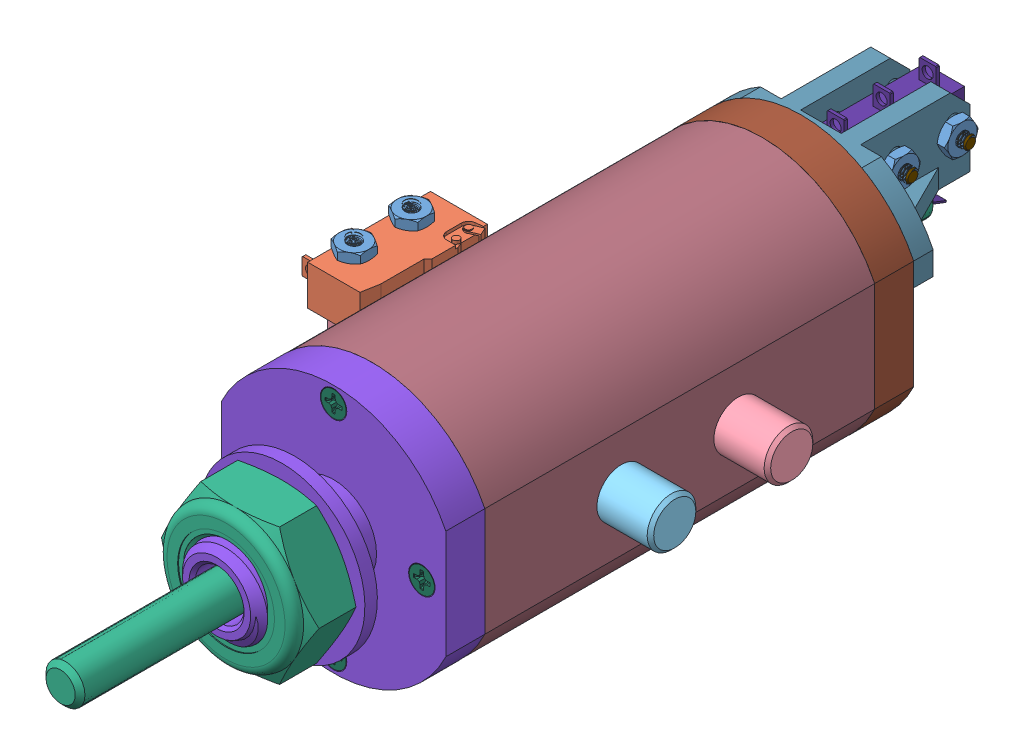
SolidWorks assembly Wing Fold Handle Mechanism, configuration Default. Lengths in mm.
Overall size (71.41 40.64 162.07).
63 component instances, 27 part files, 3 mates.
Components (placement in the parent):
- Wing Fold Mechanism Rotating ASSY-1: Wing Fold Mechanism Rotating ASSY [Default] at origin size (19.05 19.05 139.7)
  - Wing Fold Mechanism Rotary Detents-1: Wing Fold Mechanism Rotary Detents [Default] at origin size (19.05 19.05 19.05)
    - Wing Fold Mechanism Rotary Detents-1: Wing Fold Mechanism Rotary Detents [Default] at origin size (19.05 19.05 19.05)
    - 92311A105-1: 92311A105 [Default] at (-4.0904 4.0904 33.3375) x (0.707107 0.707107 0) z (-0.707107 0.707107 0) size (2.91 2.9 4.84)
    - 91841A005-1: 91841A005 [Default] at (-4.0972 4.0972 33.3375) x (0.707107 0.707107 0) z (0 0 1) size (6.35 2.56 7.33)
    - 92311A105-2: 92311A105 [Default] at (-4.0904 4.0904 23.8125) x (0.707107 0.707107 0) z (-0.707107 0.707107 0) size (2.91 2.9 4.84)
    - 91841A005-2: 91841A005 [Default] at (-4.0972 4.0972 23.8125) x (0.707107 0.707107 0) z (0 0 1) size (6.35 2.56 7.33)
  - Wing Fold Mechanism Push-Pull Detents-1: Wing Fold Mechanism Push-Pull Detents [Default] at origin size (19.05 19.05 19.05)
    - Wing Fold Mechanism Push-Pull Detents-1: Wing Fold Mechanism Push-Pull Detents [Default] at origin size (19.05 19.05 19.05)
    - 91841A005-1: 91841A005 [Default] at (-4.0972 4.0972 14.2875) x (0.707107 0.707107 0) z (0 0 1) size (6.35 2.56 7.33)
    - 92311A105-1: 92311A105 [Default] at (-4.0904 4.0904 14.2875) x (0.707107 0.707107 0) z (-0.707107 0.707107 0) size (2.91 2.9 4.84)
  - 9414T6-1: 9414T6 [Default] at (0 0 -3.5719) x (0.707107 -0.707107 0) z (0 0 1) size (12.7 12.7 7.15)
  - 9414T6-2: 9414T6 [Default] at (0 0 41.6719) size (12.7 12.7 7.15)
  - Wing Fold Mechanism .250 Shaft-1: Wing Fold Mechanism .250 Shaft [Default] at origin size (6.35 6.35 139.7)
  - 92311A425-1: 92311A425 [Default] at (4.771 4.771 -3.5719) x (0.707107 -0.707107 0) z (0.707107 0.707107 0) size (4.96 4.83 6.49)
- Wing Fold Mechanism Body-1: Wing Fold Mechanism Body [Default] at origin size (59.65 40.64 121.3)
  - Wing Fold Mechanism Upper Cap-1: Wing Fold Mechanism Upper Cap [Default] at origin size (36.58 40.64 28.08)
    - Wing Fold Mechanism Upper Cap-1: Wing Fold Mechanism Upper Cap [Default] at origin size (36.58 40.64 28.08)
    - 6338K411-1: 6338K411 [Default] at (0 0 55.5625) x (1 0 0) z (0 -1 0) size (12.7 6.35 12.7)
    - 93365A112-1: 93365A112 [Default] at (0 -11.1125 61.9125) x (1 0 0) z (0 -1 0) size (3.58 4.78 3.58)
  - Wing Fold Mechanism Lower Cap-1: Wing Fold Mechanism Lower Cap [Default] at origin size (36.58 40.64 13.97)
    - Wing Fold Mechanism Lower Cap-1: Wing Fold Mechanism Lower Cap [Default] at origin size (36.58 40.64 13.97)
    - 6338K411 (1)-1: 6338K411 (1) [Default] at (0 0 -7.9375) x (1 0 0) z (0 1 0) size (12.7 6.35 12.7)
    - 93365A112-1: 93365A112 [Default] at (11.938 11.43 -14.2875) x (1 0 0) z (0 1 0) size (3.58 4.78 3.58)
    - 93365A112-2: 93365A112 [Default] at (-11.938 11.43 -14.2875) x (1 0 0) z (0 1 0) size (3.58 4.78 3.58)
  - Wing Fold Mechanism Main Shell-1: Wing Fold Mechanism Main Shell [Default] at origin size (46.86 40.64 63.5)
    - Wing Fold Mechanism Main Body-1: Wing Fold Mechanism Main Body [Default] at origin size (46.86 40.64 63.5)
    - 93365A112-1: 93365A112 [Default] at (-14.378 0 55.5625) x (1 0 0) z (0 -1 0) size (3.58 4.78 3.58)
    - 93365A112-2: 93365A112 [Default] at (0 17.68 55.5625) x (1 0 0) z (0 -1 0) size (3.58 4.78 3.58)
    - 93365A112-3: 93365A112 [Default] at (14.378 0 55.5625) x (1 0 0) z (0 -1 0) size (3.58 4.78 3.58)
    - 93365A112-4: 93365A112 [Default] at (0 -17.68 55.5625) x (1 0 0) z (0 -1 0) size (3.58 4.78 3.58)
    - 93365A112-5: 93365A112 [Default] at (-14.378 0 -7.9375) x (1 0 0) z (0 1 0) size (3.58 4.78 3.58)
    - 93365A112-6: 93365A112 [Default] at (14.378 0 -7.9375) x (1 0 0) z (0 1 0) size (3.58 4.78 3.58)
    - 93365A112-7: 93365A112 [Default] at (0 -17.68 -7.9375) x (1 0 0) z (0 1 0) size (3.58 4.78 3.58)
    - 93365A112-8: 93365A112 [Default] at (0 17.68 -7.9375) x (1 0 0) z (0 1 0) size (3.58 4.78 3.58)
  - Wing Fold Mechanism Locking Limit Switch Bracket-1: Wing Fold Mechanism Locking Limit Switch Bracket [Default] at origin size (36.58 12.7 20.96)
  - 96640A027-1: 96640A027 [Default] at (-14.378 0 60.6171) size (4.11 4.11 12.73)
  - 96640A027-2: 96640A027 [Default] at (0 -17.68 60.6171) size (4.11 4.11 12.73)
  - 96640A027-3: 96640A027 [Default] at (0 17.68 60.6171) size (4.11 4.11 12.73)
  - 96640A027-4: 96640A027 [Default] at (14.378 0 60.6171) size (4.11 4.11 12.73)
  - 96640A027-5: 96640A027 [Default] at (0 -17.68 -12.9921) x (1 0 0) z (0 0 -1) size (4.11 4.11 12.73)
  - 96640A027-6: 96640A027 [Default] at (0 17.68 -12.9921) x (1 0 0) z (0 0 -1) size (4.11 4.11 12.73)
  - 96640A027-7: 96640A027 [Default] at (14.378 0 -12.9921) x (1 0 0) z (0 0 -1) size (4.11 4.11 12.73)
  - 96640A027-8: 96640A027 [Default] at (-14.378 0 -12.9921) x (1 0 0) z (0 0 -1) size (4.11 4.11 12.73)
  - 91249A050-1: 91249A050 [Default] at (-11.938 11.43 -11.1125) x (1 0 0) z (0 0 -1) size (4.25 4.24 8)
  - 91249A050-2: 91249A050 [Default] at (11.938 11.43 -11.1125) x (1 0 0) z (0 0 -1) size (4.25 4.24 8)
  - 7658K15-1: 7658K15 [Default] at (-0.0508 14.2684 -27.6606) x (0 0 -1) z (-1 0 0) size (19.99 19.56 6.5)
  - 91249A060-1: 91249A060 [Default] at (9.398 11.9062 -23.0505) x (0 0 -1) z (-1 0 0) size (12.29 12.29 20.87)
  - 91249A060-2: 91249A060 [Default] at (9.398 11.9062 -32.4485) x (0 0 -1) z (-1 0 0) size (12.29 12.29 20.87)
  - 91841A003-1: 91841A003 [Default] at (7.2708 11.9062 -23.0505) x (0 -1 0) z (0 0 1) size (4.76 1.72 5.5)
  - 91841A003-2: 91841A003 [Default] at (7.2708 11.9062 -32.4485) x (0 -1 0) z (0 0 1) size (4.76 1.72 5.5)
  - 7658K16-1: 7658K16 [Default] at (-28.3972 8.1042 27.7241) x (0 0 1) z (0 1 0) size (19.99 24.56 6.5)
  - 7658K16-2: 7658K16 [Default] at (-28.3972 -8.1042 27.7241) x (0 0 1) z (0 1 0) size (19.99 24.56 6.5)
  - 91249A066-1: 91249A066 [Default] at (-26.035 14.0446 23.1521) x (1 0 0) z (0 -1 0) size (12.46 12.46 36.26)
  - 91249A066-2: 91249A066 [Default] at (-26.035 14.0446 32.512) x (1 0 0) z (0 -1 0) size (12.46 12.46 36.26)
  - 91841A003-3: 91841A003 [Default] at (-26.035 12.1491 23.1521) x (-1 0 0) z (0 0 -1) size (4.76 1.72 5.5)
  - 91841A003-4: 91841A003 [Default] at (-26.035 12.1491 32.512) x (-1 0 0) z (0 0 -1) size (4.76 1.72 5.5)
  - 84835A44-1: 84835A44 [Default] at (17.1196 0 14.2875) x (0 1 0) z (0 0 -1) size (9.53 19.76 9.53)
  - 84835A36-1: 84835A36 [Default] at (17.1196 0 33.3375) x (0 1 0) z (0 0 -1) size (9.53 19.76 9.53)
- Wing Fold Handle Retaining Nut-1: Wing Fold Handle Retaining Nut [Default] at (0 0 2.032) size (25.66 23.83 11.45)
- 96640A025-1: 96640A025 [Default] at (0 -11.1125 66.9671) size (4.11 4.11 9.56)
- 92141A034-1: 92141A034 [Default] at (0 0 68.2625) x (1 0 0) z (0 -1 0) size (26.97 2.03 26.97)
- Wing Fold Handle-1: Wing Fold Handle [Default] at (0 0 68.2625) x (-1 0 0) z (0 0 1) size (61.25 15.89 43.45)
Mates (geometry in assembly coordinates):
- Concentric35: concentric anti-aligned: cylinder of Wing Fold Mechanism Rotating ASSY-1/Wing Fold Mechanism .250 Shaft-1 through (0 0 106.3625) axis (0 0 -1) radius 3.175; cylinder of Wing Fold Handle-1 through (0 0 80.9625) axis (0 0 1) radius 7.9375
- Parallel8: parallel aligned: plane of Wing Fold Mechanism Body-1/7658K16-2 through (-28.3972 -11.3554 37.719) normal (0 -1 0); plane of Wing Fold Handle-1 through (0 0 68.2625) normal (0 -1 0)
- Coincident59: coincident anti-aligned: plane of Wing Fold Mechanism Body-1/Wing Fold Mechanism Upper Cap-1/Wing Fold Mechanism Upper Cap-1 through (0 0 80.9625) normal (0 0 1); plane of Wing Fold Handle-1 through (0 0 80.9625) normal (0 0 -1)
